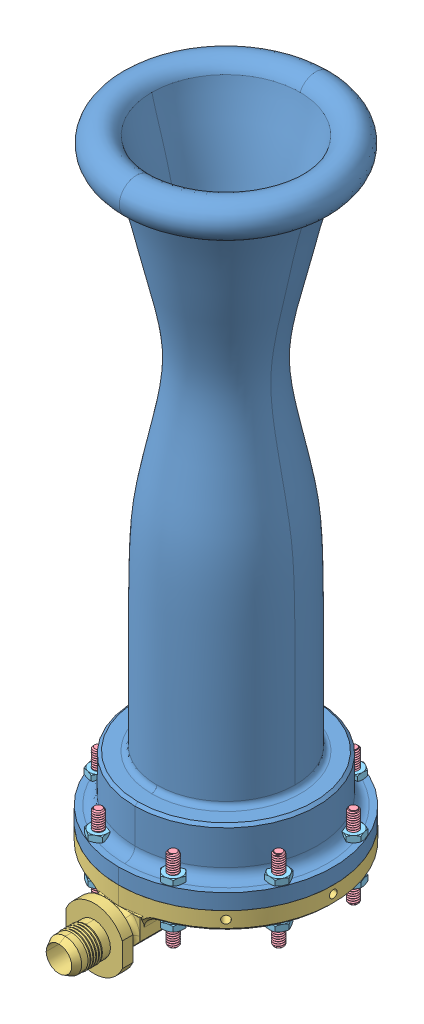
SolidWorks assembly Modified Engine Injector Assembly Jan7, configuration Default. Lengths in mm.
Overall size (133.36 416.37 180.29).
28 component instances, 5 part files, 0 mates.
Components (placement in the parent):
- Modified Engine Injector Assembly Jan7.STEP-1: Modified Engine Injector Assembly Jan7.STEP [Default] at origin size (133.36 416.37 180.29)
  - Engine ID Profile Dec26 REV.STEP-1: Engine ID Profile Dec26 REV.STEP [Default] at origin size (133.36 376.19 148.83)
  - Modified Injector Jan4.STEP-1: Modified Injector Jan4.STEP [Default] at (0 -0.3607 0) x (0 0 -1) z (-1 0 0) size (104.3 22.27 104.3)
  - Modified Oxidizer Dome.STEP-1: Modified Oxidizer Dome.STEP [Default] at (0 -22.2707 0) x (-1 0 0) z (0 0 1) size (133.36 40.17 170.4)
  - 90322A648 Double Threaded Rod_90322A648.STEP-1: 90322A648 Double Threaded Rod_90322A648.STEP [Default] at (23.1891 -22.9946 -55.9833) x (0 -1 0) z (-0.791604 0 0.611034) size (50.8 6.35 6.36)
  - 92101A210 Hex Nut_92101A210.STEP-1: 92101A210 Hex Nut_92101A210.STEP [Default] at (23.1891 -35.3676 -55.9833) size (12.84 3.99 12.86)
  - 92101A210 Hex Nut_92101A210.STEP-2: 92101A210 Hex Nut_92101A210.STEP [Default] at (23.1891 -10.6216 -55.9833) size (12.84 3.99 12.86)
  - 92101A210 Hex Nut_92101A210.STEP-3: 92101A210 Hex Nut_92101A210.STEP [Default] at (-23.1891 -10.6216 -55.9833) x (0.707107 0 -0.707107) z (0.707107 0 0.707107) size (12.84 3.99 12.86)
  - 92101A210 Hex Nut_92101A210.STEP-4: 92101A210 Hex Nut_92101A210.STEP [Default] at (-55.9833 -10.6216 -23.1891) x (0 0 -1) z (1 0 0) size (12.84 3.99 12.86)
  - 92101A210 Hex Nut_92101A210.STEP-5: 92101A210 Hex Nut_92101A210.STEP [Default] at (-55.9833 -10.6216 23.1891) x (-0.707107 0 -0.707107) z (0.707107 0 -0.707107) size (12.84 3.99 12.86)
  - 92101A210 Hex Nut_92101A210.STEP-6: 92101A210 Hex Nut_92101A210.STEP [Default] at (-23.1891 -10.6216 55.9833) x (-1 0 0) z (0 0 -1) size (12.84 3.99 12.86)
  - 92101A210 Hex Nut_92101A210.STEP-7: 92101A210 Hex Nut_92101A210.STEP [Default] at (23.1891 -10.6216 55.9833) x (-0.707107 0 0.707107) z (-0.707107 0 -0.707107) size (12.84 3.99 12.86)
  - 92101A210 Hex Nut_92101A210.STEP-8: 92101A210 Hex Nut_92101A210.STEP [Default] at (55.9833 -10.6216 23.1891) x (0 0 1) z (-1 0 0) size (12.84 3.99 12.86)
  - 92101A210 Hex Nut_92101A210.STEP-9: 92101A210 Hex Nut_92101A210.STEP [Default] at (55.9833 -10.6216 -23.1891) x (0.707107 0 0.707107) z (-0.707107 0 0.707107) size (12.84 3.99 12.86)
  - 92101A210 Hex Nut_92101A210.STEP-10: 92101A210 Hex Nut_92101A210.STEP [Default] at (-23.1891 -35.3676 -55.9833) x (0.707107 0 -0.707107) z (0.707107 0 0.707107) size (12.84 3.99 12.86)
  - 92101A210 Hex Nut_92101A210.STEP-11: 92101A210 Hex Nut_92101A210.STEP [Default] at (-55.9833 -35.3676 -23.1891) x (0 0 -1) z (1 0 0) size (12.84 3.99 12.86)
  - 92101A210 Hex Nut_92101A210.STEP-12: 92101A210 Hex Nut_92101A210.STEP [Default] at (-55.9833 -35.3676 23.1891) x (-0.707107 0 -0.707107) z (0.707107 0 -0.707107) size (12.84 3.99 12.86)
  - 92101A210 Hex Nut_92101A210.STEP-13: 92101A210 Hex Nut_92101A210.STEP [Default] at (-23.1891 -35.3676 55.9833) x (-1 0 0) z (0 0 -1) size (12.84 3.99 12.86)
  - 92101A210 Hex Nut_92101A210.STEP-14: 92101A210 Hex Nut_92101A210.STEP [Default] at (23.1891 -35.3676 55.9833) x (-0.707107 0 0.707107) z (-0.707107 0 -0.707107) size (12.84 3.99 12.86)
  - 92101A210 Hex Nut_92101A210.STEP-15: 92101A210 Hex Nut_92101A210.STEP [Default] at (55.9833 -35.3676 23.1891) x (0 0 1) z (-1 0 0) size (12.84 3.99 12.86)
  - 92101A210 Hex Nut_92101A210.STEP-16: 92101A210 Hex Nut_92101A210.STEP [Default] at (55.9833 -35.3676 -23.1891) x (0.707107 0 0.707107) z (-0.707107 0 0.707107) size (12.84 3.99 12.86)
  - 90322A648 Double Threaded Rod_90322A648.STEP-2: 90322A648 Double Threaded Rod_90322A648.STEP [Default] at (-23.1891 -22.9946 -55.9833) x (0 -1 0) z (-0.127682 0 0.991815) size (50.8 6.35 6.36)
  - 90322A648 Double Threaded Rod_90322A648.STEP-3: 90322A648 Double Threaded Rod_90322A648.STEP [Default] at (-55.9833 -22.9946 -23.1891) x (0 -1 0) z (0.611034 0 0.791604) size (50.8 6.35 6.36)
  - 90322A648 Double Threaded Rod_90322A648.STEP-4: 90322A648 Double Threaded Rod_90322A648.STEP [Default] at (-55.9833 -22.9946 23.1891) x (0 -1 0) z (0.991815 0 0.127682) size (50.8 6.35 6.36)
  - 90322A648 Double Threaded Rod_90322A648.STEP-5: 90322A648 Double Threaded Rod_90322A648.STEP [Default] at (-23.1891 -22.9946 55.9833) x (0 -1 0) z (0.791604 0 -0.611034) size (50.8 6.35 6.36)
  - 90322A648 Double Threaded Rod_90322A648.STEP-6: 90322A648 Double Threaded Rod_90322A648.STEP [Default] at (23.1891 -22.9946 55.9833) x (0 -1 0) z (0.127682 0 -0.991815) size (50.8 6.35 6.36)
  - 90322A648 Double Threaded Rod_90322A648.STEP-7: 90322A648 Double Threaded Rod_90322A648.STEP [Default] at (55.9833 -22.9946 23.1891) x (0 -1 0) z (-0.611034 0 -0.791604) size (50.8 6.35 6.36)
  - 90322A648 Double Threaded Rod_90322A648.STEP-8: 90322A648 Double Threaded Rod_90322A648.STEP [Default] at (55.9833 -22.9946 -23.1891) x (0 -1 0) z (-0.991815 0 -0.127682) size (50.8 6.35 6.36)
